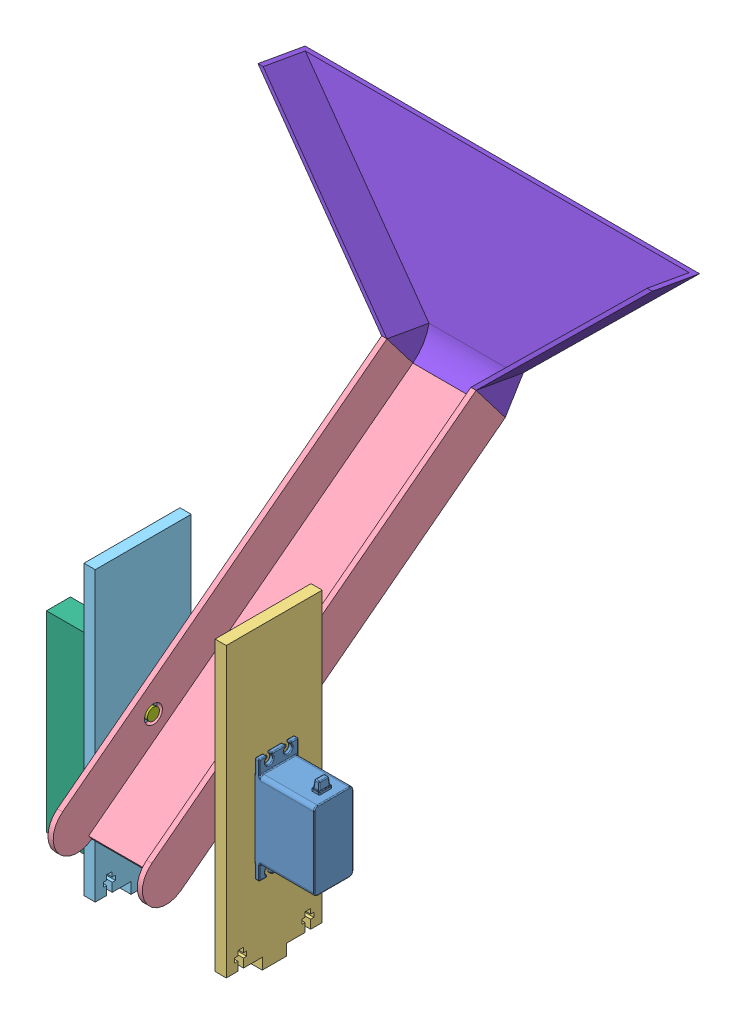
SolidWorks assembly Assem1, configuration Default. Lengths in mm.
Overall size (208.74 270.54 220.63).
8 component instances, 8 part files, 17 mates.
Components (placement in the parent):
- Servo SpringRC Rev1-1: Servo SpringRC Rev1 [Default] at (-74.825 -21.7734 20.8739) size (46.2 55.75 20.86)
- hs-422_horn_2wings_sws-4: hs-422_horn_2wings_sws [Default] at (-80.825 9.5266 31.2239) x (0 0.795009 0.606598) z (0 -0.606598 0.795009) size (9.1 5 34)
- Support1-1: Support1 [Default] at (-71.9686 -66.6731 56.716) x (0 0 -1) z (1 0 0) size (50.8 158.34 5.94)
- Arm-1: Arm [Default] at (-85.5936 -31.3852 63.9066) x (0 0.606598 -0.795009) z (1 0 0) size (228.6 25.4 49.99)
- Support2-1: Support2 [Default] at (-141.4117 -66.6734 5.8239) x (0 1 0) z (1 0 0) size (158.34 50.8 5.94)
- Scoop shaft support-1: Scoop shaft support [Default] at (-142.2549 -66.6734 12.1739) x (-1 0 0) z (0 0 -1) size (38.1 101.6 25.4)
- 2 inch shaft-1: 2 inch shaft [Default] at (-180.8436 9.5266 31.2239) x (0 0.757426 0.652921) z (1 0 0) size (6.35 6.35 50.8)
- Scooper-1: Scooper [Default] at (-85.5936 115.3285 -117.3365) x (-1 0 0) z (0 0.984576 -0.17496) size (208.74 25.4 96.56)
Mates (geometry in assembly coordinates):
- Concentric2: concentric: cylinder of Servo SpringRC Rev1-1 through (-80.825 9.5266 31.2239) axis (1 0 0) radius 3; cylinder of hs-422_horn_2wings_sws-4 through (-78.325 9.5266 31.2239) axis (-1 0 0) radius 2.5
- Coincident2: coincident: plane of Servo SpringRC Rev1-1 through (-80.825 9.5266 31.2239) normal (-1 0 0); plane of hs-422_horn_2wings_sws-4 through (-80.825 18.3223 19.6963) normal (1 0 0)
- Coincident5: coincident: plane of Servo SpringRC Rev1-1 through (-66.025 26.7516 20.8739) normal (-1 0 0); plane of Support1-1 through (-66.025 -66.6731 56.716) normal (1 0 0)
- Concentric3: concentric: cylinder of hs-422_horn_2wings_sws-4 through (-83.325 9.5266 31.2239) axis (1 0 0) radius 3.75; cylinder of Arm-1 through (-85.5936 9.5266 31.2239) axis (1 0 0) radius 3.81
- Coincident6: coincident: plane of hs-422_horn_2wings_sws-4 through (-82.825 18.3223 19.6963) normal (-1 0 0); plane of Arm-1 through (-82.825 -21.2885 71.6104) normal (1 0 0)
- Parallel2: parallel: line of hs-422_horn_2wings_sws-4 through (-78.325 9.5266 31.2239) axis (0 -0.606598 0.795009); line of Arm-1 through (-85.5936 119.7725 -92.3283) axis (0 -0.606598 0.795009)
- Parallel3: parallel: plane of Support1-1 through (-71.9686 -66.6731 56.716) normal (-1 0 0); plane of Support2-1 through (-135.4681 -66.6734 5.8239) normal (1 0 0)
- Parallel4: parallel: plane of Support1-1 through (-66.025 85.7269 56.716) normal (0 1 0); plane of Support2-1 through (-135.4681 85.7266 5.8239) normal (0 1 0)
- Concentric5: concentric: circle of Arm-1; circle of Support2-1
- Concentric6: concentric: circle of Support2-1; circle of Scoop shaft support-1
- Concentric7: concentric: circle of Arm-1; circle of 2 inch shaft-1
- Coincident13: coincident: plane of Arm-1 through (-130.0436 -21.2885 71.6104) normal (1 0 0); plane of 2 inch shaft-1 through (-130.0436 9.5266 31.2239) normal (1 0 0)
- Coincident18: coincident: plane of Servo SpringRC Rev1-1 through (-34.625 19.5266 41.5739) normal (0 0 1); plane of Support1-1 through (-71.9686 19.5266 41.5739) normal (0 0 -1)
- Distance3: distance = 73.2003 mm: cylinder of Servo SpringRC Rev1-1 through (-80.825 9.5266 31.2239) axis (1 0 0) radius 3; plane of Support1-1 through (-66.025 85.7269 56.716) normal (0 1 0)
- Coincident26: coincident: plane of Arm-1 through (-82.825 99.5793 -107.7359) normal (0 0.606598 -0.795009); plane of Scooper-1 through (-94.1226 119.7725 -92.3283) normal (0 -0.606598 0.795009)
- Coincident27: coincident: plane of Arm-1 through (-132.8122 -21.2885 71.6104) normal (-1 0 0); plane of Scooper-1 through (-132.8122 90.3203 -112.8926) normal (-1 0 0)
- Coincident28: coincident: line of Arm-1 through (-82.825 99.5793 -107.7359) axis (-1 0 0); line of Scooper-1 through (-82.825 99.5793 -107.7359) axis (-1 0 0)
